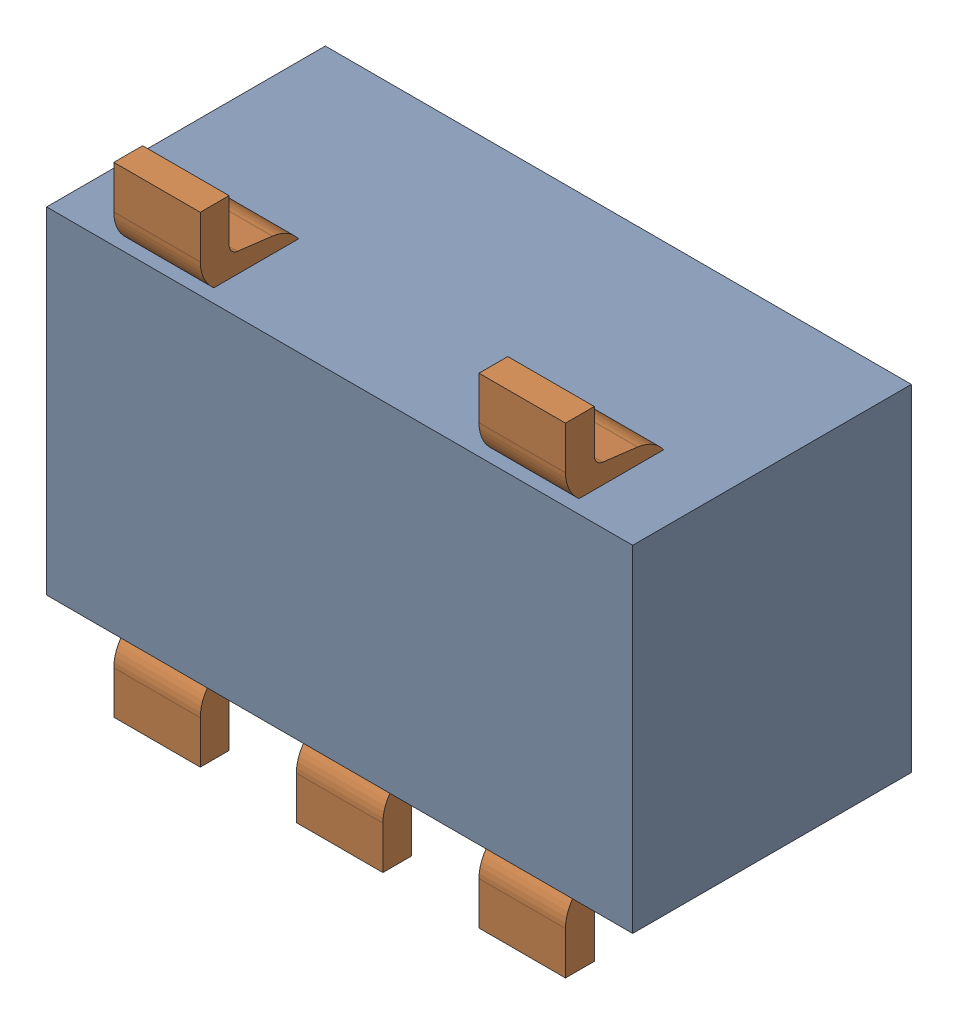
SolidWorks assembly U7, configuration Default. Lengths in mm.
Overall size (3.05 2.5 1.45).
3 component instances, 2 part files, 0 mates.
Components (placement in the parent):
- 1088885384-1: 1088885384 [Default] at (6.575 20.025 -3.094) size (3.05 1.75 1.45)
  - Extruded-22-1: Extruded-22 [Default] at origin size (3.05 1.75 1.45)
- SOT23-5L-1: SOT23-5L [Default] at (6.5749 20.0251 -2.194) x (-1 0 0) z (0 -1 0) size (3 1.1 2.5)
